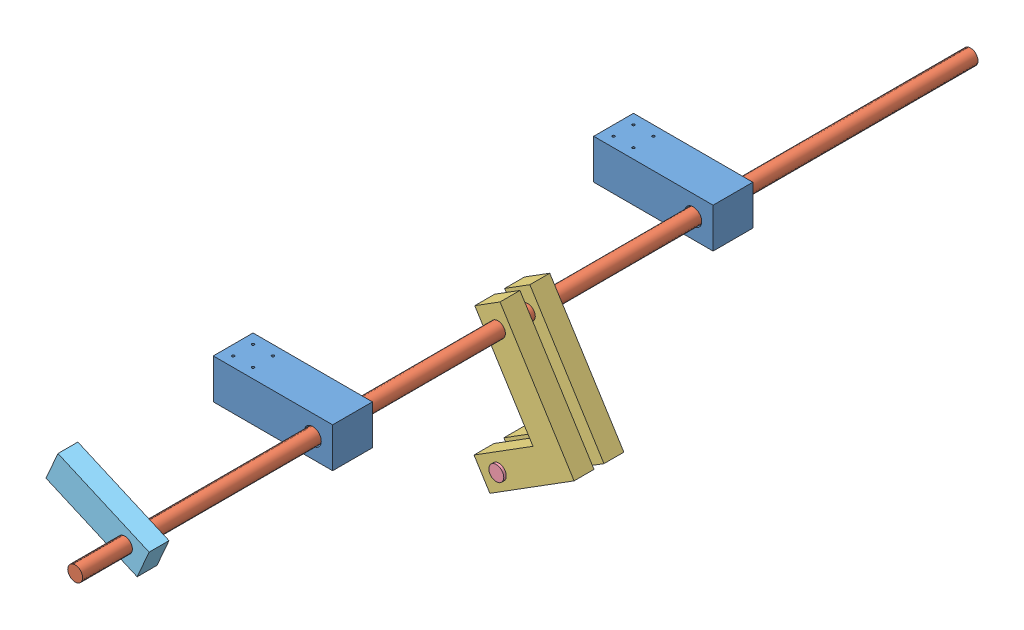
SolidWorks assembly Release Mechanism, configuration Default. Lengths in mm.
Overall size (224.2 244.6 1143).
7 component instances, 5 part files, 15 mates.
Components (placement in the parent):
- Release support-1: Release support [Default] at (5.6069 50.7445 80.7306) x (0 0 1) z (-1 0 0) size (50.8 50.8 152.4)
- Release support-2: Release support [Default] at (5.6069 50.7445 -404.9174) x (0 0 1) z (-1 0 0) size (50.8 50.8 152.4)
- Release Dowel-1: Release Dowel [Default] at (132.6069 76.1445 -708.1934) size (19.05 19.05 1143)
- RELEASE HOOK-1: RELEASE HOOK [Default] at (102.964 87.5183 -168.4434) x (0.531967 -0.846765 0) z (0 0 1) size (177.8 127 25.4)
- RELEASE HOOK-2: RELEASE HOOK [Default] at (102.964 87.5183 -130.3434) x (0.531967 -0.846765 0) z (0 0 1) size (177.8 127 25.4)
- Hook Dowel-1: Hook Dowel [Default] at (133.6443 -80.6855 -171.6184) size (19.05 19.05 69.85)
- Release Lever-1: Release Lever [Default] at (47.1299 134.2749 345.9066) x (0 0 1) z (0.916371 -0.400331 0) size (25.4 38.1 127)
Mates (geometry in assembly coordinates):
- Parallel1: parallel: line of Release support-1 through (158.0069 101.5445 80.7306) axis (-1 0 0); line of Release support-2 through (158.0069 101.5445 -354.1174) axis (-1 0 0)
- Parallel2: parallel: line of Release support-1 through (158.0069 50.7445 80.7306) axis (0 1 0); line of Release support-2 through (158.0069 50.7445 -354.1174) axis (0 1 0)
- Distance2: distance = 434.848 mm: plane of Release support-1 through (5.6069 50.7445 80.7306) normal (0 0 -1); plane of Release support-2 through (5.6069 50.7445 -354.1174) normal (0 0 1)
- Coincident5: coincident: line of Release support-1 through (158.0069 101.5445 131.5306) axis (0 0 -1); line of Release support-2 through (158.0069 101.5445 -354.1174) axis (0 0 -1)
- Concentric1: concentric: circle of Release support-1; cylinder of Release Dowel-1 through (132.6069 76.1445 434.8066) axis (0 0 -1) radius 9.525
- Width1: width: plane of Release support-1 through (5.6069 50.7445 131.5306) normal (0 0 1); plane of Release support-2 through (5.6069 50.7445 -404.9174) normal (0 0 -1); plane of Release Dowel-1 through (132.6069 76.1445 -708.1934) normal (0 0 -1); plane of Release Dowel-1 through (132.6069 76.1445 434.8066) normal (0 0 1)
- Coincident8: coincident: cylinder of Release Dowel-1 through (132.6069 76.1445 434.8066) axis (0 0 -1) radius 9.525; circle of RELEASE HOOK-1
- Coincident9: coincident: cylinder of Release Dowel-1 through (132.6069 76.1445 434.8066) axis (0 0 -1) radius 9.525; circle of RELEASE HOOK-2
- Width2: width: plane of Release support-1 through (5.6069 50.7445 80.7306) normal (0 0 -1); plane of Release support-2 through (5.6069 50.7445 -354.1174) normal (0 0 1); plane of RELEASE HOOK-2 through (102.964 87.5183 -104.9434) normal (0 0 1); plane of RELEASE HOOK-1 through (102.964 87.5183 -168.4434) normal (0 0 -1)
- Coincident12: coincident: plane of RELEASE HOOK-1 through (197.5478 -63.0365 -143.0434) normal (0.531967 -0.846765 0); plane of RELEASE HOOK-2 through (197.5478 -63.0365 -104.9434) normal (0.531967 -0.846765 0)
- Concentric2: concentric: cylinder of RELEASE HOOK-2 through (133.6443 -80.6855 -130.3434) axis (0 0 1) radius 9.525; cylinder of Hook Dowel-1 through (133.6443 -80.6855 -101.7684) axis (0 0 -1) radius 9.525
- Width3: width: plane of RELEASE HOOK-2 through (102.964 87.5183 -104.9434) normal (0 0 1); plane of RELEASE HOOK-1 through (102.964 87.5183 -168.4434) normal (0 0 -1); plane of Hook Dowel-1 through (133.6443 -80.6855 -171.6184) normal (0 0 -1); plane of Hook Dowel-1 through (133.6443 -80.6855 -101.7684) normal (0 0 1)
- Coincident13: coincident: cylinder of Release Dowel-1 through (132.6069 76.1445 434.8066) axis (0 0 -1) radius 9.525; circle of Release Lever-1
- Distance4: distance = 63.5 mm: plane of Release Dowel-1 through (132.6069 76.1445 434.8066) normal (0 0 1); plane of Release Lever-1 through (163.509 83.4329 371.3066) normal (0 0 1)
- Distance5: distance = 12.7 mm: plane of RELEASE HOOK-2 through (102.964 87.5183 -130.3434) normal (0 0 -1); plane of RELEASE HOOK-1 through (102.964 87.5183 -143.0434) normal (0 0 1)
